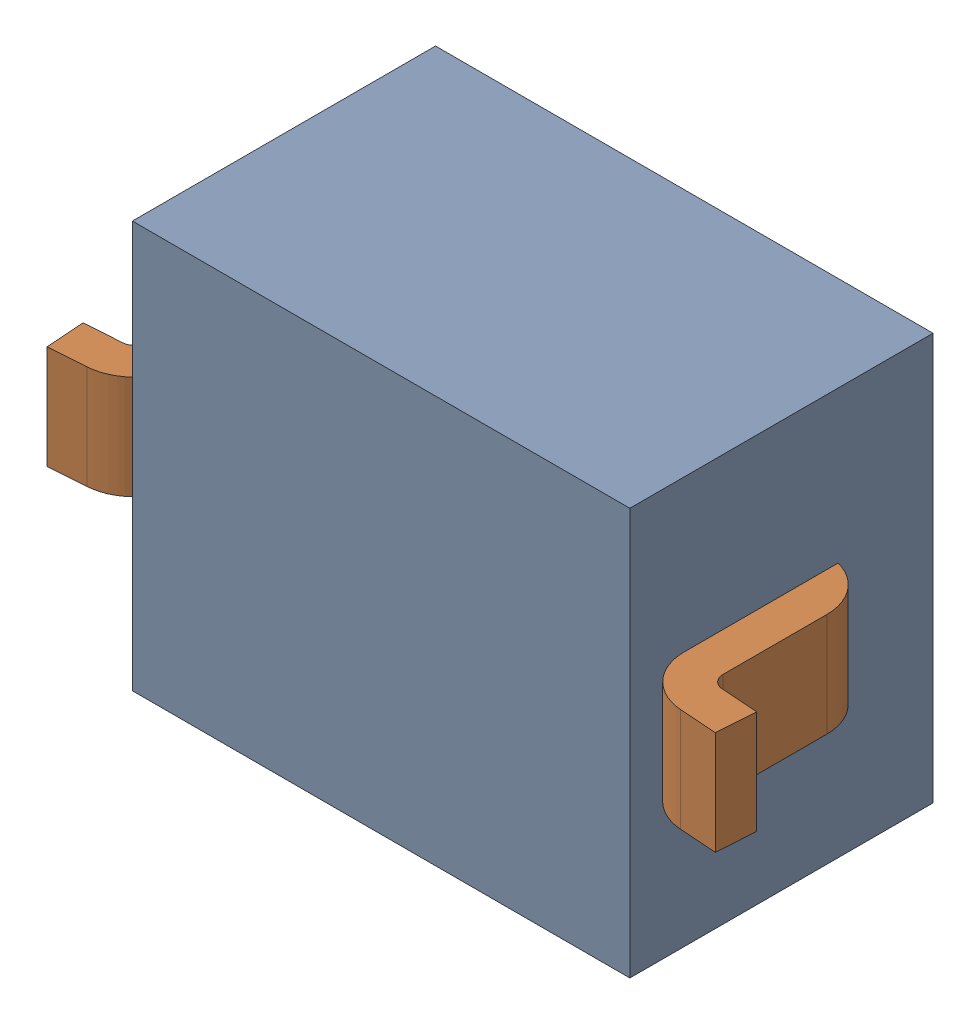
SolidWorks assembly D1, configuration Default. Lengths in mm.
Overall size (2.6 1.57 1.17).
3 component instances, 2 part files, 0 mates.
Components (placement in the parent):
- 1737248736-1: 1737248736 [Default] at (10.15 20.925 -2.814) size (1.92 1.57 1.17)
  - Extruded-39-1: Extruded-39 [Default] at origin size (1.92 1.57 1.17)
- SOD323-1: SOD323 [Default] at (10.1501 20.9249 -1.644) x (-1 0 0) z (0 0 -1) size (2.6 1.35 1.1)
